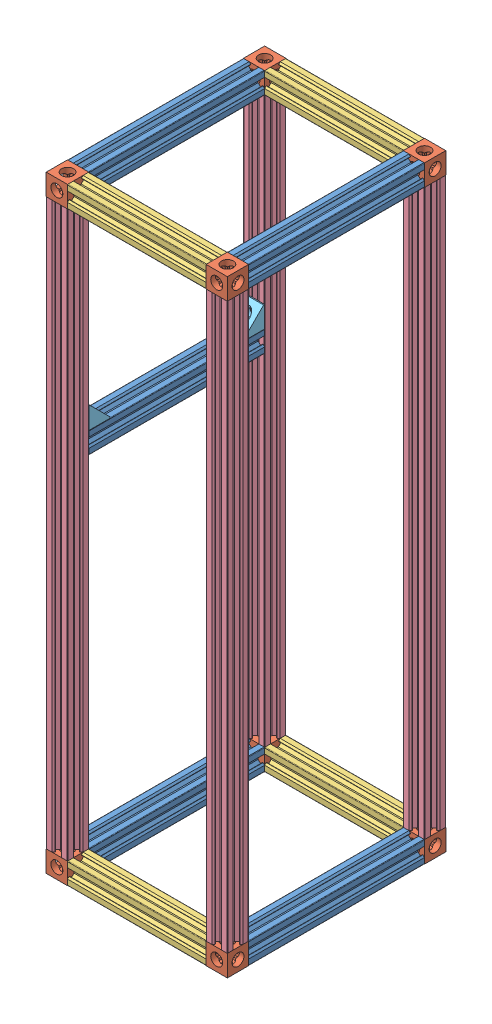
SolidWorks assembly Control Box, configuration Default. Lengths in mm.
Overall size (170 570 205).
23 component instances, 5 part files, 66 mates.
Components (placement in the parent):
- V-Slot 20x20x165-1: V-Slot 20x20x165 [Default] at (106.9043 53.7169 42.2447) size (20 20 165)
- Cube Corner Connector-1: Cube Corner Connector [Default] at (81.3908 81.0191 212.159) size (20 20 20)
- Cube Corner Connector-2: Cube Corner Connector [Default] at (81.3908 81.0191 27.159) size (20 20 20)
- V-Slot 20x20x130-1: V-Slot 20x20x130 [Default] at (-53.5235 53.7169 186.6455) x (0 0 -1) z (1 0 0) size (20 20 130)
- V-Slot 20x20x130-2: V-Slot 20x20x130 [Default] at (-53.5235 53.7169 1.6455) x (0 0 -1) z (1 0 0) size (20 20 130)
- V-Slot 20x20x165-2: V-Slot 20x20x165 [Default] at (-43.0957 53.7169 42.2447) size (20 20 165)
- Cube Corner Connector-3: Cube Corner Connector [Default] at (-68.6092 81.0191 212.159) x (0 1 0) z (0 0 1) size (20 20 20)
- Cube Corner Connector-4: Cube Corner Connector [Default] at (-68.6092 81.0191 27.159) x (0 -1 0) z (0 0 -1) size (20 20 20)
- V-Slot 20x20x530-1: V-Slot 20x20x530 [Default] at (55.142 551.2333 173.9853) x (1 0 0) z (0 -1 0) size (20 20 530)
- V-Slot 20x20x530-2: V-Slot 20x20x530 [Default] at (55.142 551.2333 -11.0147) x (1 0 0) z (0 -1 0) size (20 20 530)
- V-Slot 20x20x530-3: V-Slot 20x20x530 [Default] at (-94.858 160.805 250.3328) x (1 0 0) z (0 1 0) size (20 20 530)
- V-Slot 20x20x530-4: V-Slot 20x20x530 [Default] at (-94.858 160.805 65.3328) x (1 0 0) z (0 1 0) size (20 20 530)
- Cube Corner Connector-5: Cube Corner Connector [Default] at (-68.6092 631.0191 27.159) size (20 20 20)
- Cube Corner Connector-6: Cube Corner Connector [Default] at (-68.6092 631.0191 212.159) x (0 0 1) z (-1 0 0) size (20 20 20)
- Cube Corner Connector-7: Cube Corner Connector [Default] at (81.3908 631.0191 212.159) size (20 20 20)
- Cube Corner Connector-8: Cube Corner Connector [Default] at (81.3908 631.0191 27.159) size (20 20 20)
- V-Slot 20x20x130-3: V-Slot 20x20x130 [Default] at (-53.5235 603.7169 1.6455) x (0 0 -1) z (1 0 0) size (20 20 130)
- V-Slot 20x20x130-4: V-Slot 20x20x130 [Default] at (-53.5235 603.7169 186.6455) x (0 0 -1) z (1 0 0) size (20 20 130)
- V-Slot 20x20x165-3: V-Slot 20x20x165 [Default] at (106.9043 603.7169 42.2447) size (20 20 165)
- V-Slot 20x20x165-4: V-Slot 20x20x165 [Default] at (-43.0957 603.7169 42.2447) size (20 20 165)
- V-Slot 20x20x165-5: V-Slot 20x20x165 [Default] at (-43.0957 393.7169 42.2447) size (20 20 165)
- Black Angle Corner Connector-1: Black Angle Corner Connector [Default] at (-68.6092 441.0191 192.159) x (-1 0 0) z (0 0 -1) size (20 20 20)
- Black Angle Corner Connector-2: Black Angle Corner Connector [Default] at (-68.6092 441.0191 47.159) size (20 20 20)
Mates (geometry in assembly coordinates):
- Coincident1: coincident aligned: plane of V-Slot 20x20x165-1 through (81.3908 91.0191 537.159) normal (0 1 0); plane of Cube Corner Connector-1 through (91.3908 91.0191 222.159) normal (0 1 0)
- Coincident2: coincident aligned: plane of V-Slot 20x20x165-1 through (91.3908 81.0191 537.159) normal (1 0 0); plane of Cube Corner Connector-1 through (91.3908 71.0191 222.159) normal (1 0 0)
- Coincident3: coincident anti-aligned: plane of V-Slot 20x20x165-1 through (71.3908 71.0191 202.159) normal (0 0 1); plane of Cube Corner Connector-1 through (81.3908 81.0191 202.159) normal (0 0 -1)
- Coincident4: coincident anti-aligned: plane of V-Slot 20x20x165-1 through (81.3908 81.0191 37.159) normal (0 0 -1); plane of Cube Corner Connector-2 through (81.3908 81.0191 37.159) normal (0 0 1)
- Coincident5: coincident aligned: plane of V-Slot 20x20x165-1 through (81.3908 91.0191 537.159) normal (0 1 0); plane of Cube Corner Connector-2 through (91.3908 91.0191 37.159) normal (0 1 0)
- Coincident7: coincident aligned: plane of V-Slot 20x20x165-1 through (91.3908 81.0191 537.159) normal (1 0 0); plane of Cube Corner Connector-2 through (91.3908 71.0191 37.159) normal (1 0 0)
- Coincident8: coincident anti-aligned: plane of Cube Corner Connector-1 through (71.3908 71.0191 222.159) normal (-1 0 0); plane of V-Slot 20x20x130-1 through (71.3908 71.0191 222.159) normal (1 0 0)
- Coincident9: coincident aligned: plane of Cube Corner Connector-1 through (81.3908 81.0191 222.159) normal (0 0 1); plane of V-Slot 20x20x130-1 through (441.3908 81.0191 222.159) normal (0 0 1)
- Coincident10: coincident aligned: plane of Cube Corner Connector-1 through (91.3908 91.0191 222.159) normal (0 1 0); plane of V-Slot 20x20x130-1 through (441.3908 91.0191 212.159) normal (0 1 0)
- Coincident11: coincident anti-aligned: plane of Cube Corner Connector-2 through (71.3908 71.0191 37.159) normal (-1 0 0); plane of V-Slot 20x20x130-2 through (71.3908 71.0191 37.159) normal (1 0 0)
- Coincident12: coincident aligned: plane of Cube Corner Connector-2 through (91.3908 91.0191 37.159) normal (0 1 0); plane of V-Slot 20x20x130-2 through (441.3908 91.0191 27.159) normal (0 1 0)
- Coincident13: coincident aligned: plane of Cube Corner Connector-2 through (81.3908 81.0191 17.159) normal (0 0 -1); plane of V-Slot 20x20x130-2 through (441.3908 81.0191 17.159) normal (0 0 -1)
- Coincident14: coincident anti-aligned: plane of V-Slot 20x20x130-1 through (-58.6092 81.0191 212.159) normal (-1 0 0); plane of Cube Corner Connector-3 through (-58.6092 91.0191 222.159) normal (1 0 0)
- Coincident15: coincident aligned: plane of V-Slot 20x20x130-1 through (441.3908 91.0191 212.159) normal (0 1 0); plane of Cube Corner Connector-3 through (-58.6092 91.0191 222.159) normal (0 1 0)
- Coincident16: coincident aligned: plane of V-Slot 20x20x130-1 through (441.3908 81.0191 202.159) normal (0 0 -1); plane of Cube Corner Connector-3 through (-68.6092 81.0191 202.159) normal (0 0 -1)
- Coincident17: coincident aligned: plane of V-Slot 20x20x130-2 through (441.3908 91.0191 27.159) normal (0 1 0); plane of Cube Corner Connector-4 through (-58.6092 91.0191 17.159) normal (0 1 0)
- Coincident19: coincident anti-aligned: plane of V-Slot 20x20x130-2 through (-58.6092 81.0191 27.159) normal (-1 0 0); plane of Cube Corner Connector-4 through (-58.6092 71.0191 17.159) normal (1 0 0)
- Coincident20: coincident aligned: plane of V-Slot 20x20x130-2 through (441.3908 81.0191 37.159) normal (0 0 1); plane of Cube Corner Connector-4 through (-68.6092 81.0191 37.159) normal (0 0 1)
- Coincident21: coincident anti-aligned: plane of V-Slot 20x20x165-2 through (-68.6092 81.0191 37.159) normal (0 0 -1); plane of Cube Corner Connector-4 through (-68.6092 81.0191 37.159) normal (0 0 1)
- Coincident22: coincident aligned: plane of V-Slot 20x20x165-2 through (-68.6092 91.0191 537.159) normal (0 1 0); plane of Cube Corner Connector-4 through (-58.6092 91.0191 17.159) normal (0 1 0)
- Coincident23: coincident aligned: plane of V-Slot 20x20x165-2 through (-78.6092 81.0191 537.159) normal (-1 0 0); plane of Cube Corner Connector-4 through (-78.6092 71.0191 17.159) normal (-1 0 0)
- Coincident24: coincident anti-aligned: plane of Cube Corner Connector-4 through (-58.6092 91.0191 17.159) normal (0 1 0); plane of V-Slot 20x20x530-4 through (-59.1092 91.0191 36.659) normal (0 -1 0)
- Coincident25: coincident aligned: plane of Cube Corner Connector-4 through (-68.6092 81.0191 17.159) normal (0 0 -1); plane of V-Slot 20x20x530-4 through (-68.6092 621.0191 17.159) normal (0 0 -1)
- Coincident26: coincident aligned: plane of Cube Corner Connector-4 through (-78.6092 71.0191 17.159) normal (-1 0 0); plane of V-Slot 20x20x530-4 through (-78.6092 621.0191 27.159) normal (-1 0 0)
- Coincident27: coincident anti-aligned: plane of Cube Corner Connector-3 through (-58.6092 91.0191 222.159) normal (0 1 0); plane of V-Slot 20x20x530-3 through (-59.1092 91.0191 221.659) normal (0 -1 0)
- Coincident28: coincident aligned: plane of Cube Corner Connector-3 through (-78.6092 91.0191 222.159) normal (-1 0 0); plane of V-Slot 20x20x530-3 through (-78.6092 621.0191 212.159) normal (-1 0 0)
- Coincident29: coincident aligned: plane of Cube Corner Connector-3 through (-68.6092 81.0191 222.159) normal (0 0 1); plane of V-Slot 20x20x530-3 through (-68.6092 621.0191 222.159) normal (0 0 1)
- Coincident30: coincident anti-aligned: plane of Cube Corner Connector-1 through (91.3908 91.0191 222.159) normal (0 1 0); plane of V-Slot 20x20x530-1 through (81.3908 91.0191 212.159) normal (0 -1 0)
- Coincident31: coincident aligned: plane of Cube Corner Connector-1 through (71.3908 71.0191 222.159) normal (-1 0 0); plane of V-Slot 20x20x530-1 through (71.3908 91.0191 212.159) normal (-1 0 0)
- Coincident32: coincident aligned: plane of Cube Corner Connector-1 through (81.3908 81.0191 222.159) normal (0 0 1); plane of V-Slot 20x20x530-1 through (81.3908 91.0191 222.159) normal (0 0 1)
- Coincident33: coincident anti-aligned: plane of Cube Corner Connector-2 through (91.3908 91.0191 37.159) normal (0 1 0); plane of V-Slot 20x20x530-2 through (81.3908 91.0191 27.159) normal (0 -1 0)
- Coincident34: coincident aligned: plane of Cube Corner Connector-2 through (81.3908 81.0191 17.159) normal (0 0 -1); plane of V-Slot 20x20x530-2 through (81.3908 91.0191 17.159) normal (0 0 -1)
- Coincident35: coincident aligned: plane of Cube Corner Connector-2 through (91.3908 71.0191 37.159) normal (1 0 0); plane of V-Slot 20x20x530-2 through (91.3908 91.0191 27.159) normal (1 0 0)
- Coincident36: coincident aligned: plane of V-Slot 20x20x530-4 through (-68.6092 621.0191 17.159) normal (0 0 -1); plane of Cube Corner Connector-5 through (-68.6092 631.0191 17.159) normal (0 0 -1)
- Coincident37: coincident aligned: plane of V-Slot 20x20x530-4 through (-78.6092 621.0191 27.159) normal (-1 0 0); plane of Cube Corner Connector-5 through (-78.6092 621.0191 37.159) normal (-1 0 0)
- Coincident38: coincident anti-aligned: plane of V-Slot 20x20x530-4 through (-68.6092 621.0191 27.159) normal (0 1 0); plane of Cube Corner Connector-5 through (-58.6092 621.0191 37.159) normal (0 -1 0)
- Coincident40: coincident anti-aligned: plane of V-Slot 20x20x530-3 through (-68.6092 621.0191 212.159) normal (0 1 0); plane of Cube Corner Connector-6 through (-78.6092 621.0191 222.159) normal (0 -1 0)
- Coincident41: coincident aligned: plane of V-Slot 20x20x530-3 through (-78.6092 621.0191 212.159) normal (-1 0 0); plane of Cube Corner Connector-6 through (-78.6092 631.0191 212.159) normal (-1 0 0)
- Coincident42: coincident aligned: plane of V-Slot 20x20x530-3 through (-68.6092 621.0191 202.159) normal (0 0 -1); plane of Cube Corner Connector-6 through (-78.6092 621.0191 202.159) normal (0 0 -1)
- Coincident43: coincident aligned: plane of V-Slot 20x20x530-1 through (81.3908 91.0191 202.159) normal (0 0 -1); plane of Cube Corner Connector-7 through (81.3908 631.0191 202.159) normal (0 0 -1)
- Coincident44: coincident aligned: plane of V-Slot 20x20x530-1 through (71.3908 91.0191 212.159) normal (-1 0 0); plane of Cube Corner Connector-7 through (71.3908 621.0191 222.159) normal (-1 0 0)
- Coincident45: coincident anti-aligned: plane of V-Slot 20x20x530-1 through (90.8908 621.0191 202.659) normal (0 1 0); plane of Cube Corner Connector-7 through (91.3908 621.0191 222.159) normal (0 -1 0)
- Coincident46: coincident aligned: plane of V-Slot 20x20x530-2 through (81.3908 91.0191 17.159) normal (0 0 -1); plane of Cube Corner Connector-8 through (81.3908 631.0191 17.159) normal (0 0 -1)
- Coincident47: coincident aligned: plane of V-Slot 20x20x530-2 through (71.3908 91.0191 27.159) normal (-1 0 0); plane of Cube Corner Connector-8 through (71.3908 621.0191 37.159) normal (-1 0 0)
- Coincident48: coincident anti-aligned: plane of V-Slot 20x20x530-2 through (90.8908 621.0191 17.659) normal (0 1 0); plane of Cube Corner Connector-8 through (91.3908 621.0191 37.159) normal (0 -1 0)
- Coincident49: coincident anti-aligned: plane of Cube Corner Connector-5 through (-58.6092 621.0191 37.159) normal (1 0 0); plane of V-Slot 20x20x130-3 through (-58.6092 631.0191 27.159) normal (-1 0 0)
- Coincident50: coincident aligned: plane of Cube Corner Connector-5 through (-68.6092 631.0191 17.159) normal (0 0 -1); plane of V-Slot 20x20x130-3 through (441.3908 631.0191 17.159) normal (0 0 -1)
- Coincident51: coincident aligned: plane of Cube Corner Connector-5 through (-58.6092 641.0191 37.159) normal (0 1 0); plane of V-Slot 20x20x130-3 through (441.3908 641.0191 27.159) normal (0 1 0)
- Coincident52: coincident aligned: plane of Cube Corner Connector-6 through (-78.6092 641.0191 222.159) normal (0 1 0); plane of V-Slot 20x20x130-4 through (441.3908 641.0191 212.159) normal (0 1 0)
- Coincident53: coincident anti-aligned: plane of Cube Corner Connector-6 through (-58.6092 631.0191 212.159) normal (1 0 0); plane of V-Slot 20x20x130-4 through (-58.6092 631.0191 212.159) normal (-1 0 0)
- Coincident54: coincident aligned: plane of Cube Corner Connector-6 through (-78.6092 621.0191 202.159) normal (0 0 -1); plane of V-Slot 20x20x130-4 through (441.3908 631.0191 202.159) normal (0 0 -1)
- Coincident55: coincident anti-aligned: plane of Cube Corner Connector-5 through (-68.6092 631.0191 37.159) normal (0 0 1); plane of V-Slot 20x20x165-4 through (-68.6092 631.0191 37.159) normal (0 0 -1)
- Coincident56: coincident aligned: plane of Cube Corner Connector-5 through (-78.6092 621.0191 37.159) normal (-1 0 0); plane of V-Slot 20x20x165-4 through (-78.6092 631.0191 537.159) normal (-1 0 0)
- Coincident57: coincident aligned: plane of Cube Corner Connector-5 through (-58.6092 641.0191 37.159) normal (0 1 0); plane of V-Slot 20x20x165-4 through (-68.6092 641.0191 537.159) normal (0 1 0)
- Coincident58: coincident aligned: plane of Cube Corner Connector-8 through (91.3908 641.0191 37.159) normal (0 1 0); plane of V-Slot 20x20x165-3 through (81.3908 641.0191 537.159) normal (0 1 0)
- Coincident59: coincident aligned: plane of Cube Corner Connector-8 through (71.3908 621.0191 37.159) normal (-1 0 0); plane of V-Slot 20x20x165-3 through (71.3908 631.0191 537.159) normal (-1 0 0)
- Coincident60: coincident anti-aligned: plane of Cube Corner Connector-7 through (81.3908 631.0191 202.159) normal (0 0 -1); plane of V-Slot 20x20x165-3 through (71.3908 621.0191 202.159) normal (0 0 1)
- Coincident61: coincident anti-aligned: plane of V-Slot 20x20x530-3 through (-68.6092 621.0191 202.159) normal (0 0 -1); plane of V-Slot 20x20x165-5 through (-78.6092 411.0191 202.159) normal (0 0 1)
- Coincident62: coincident aligned: plane of V-Slot 20x20x530-4 through (-78.6092 621.0191 27.159) normal (-1 0 0); plane of V-Slot 20x20x165-5 through (-78.6092 421.0191 537.159) normal (-1 0 0)
- Distance1: distance = 190 mm anti-aligned: plane of V-Slot 20x20x165-4 through (-68.6092 621.0191 537.159) normal (0 -1 0); plane of V-Slot 20x20x165-5 through (-68.6092 431.0191 537.159) normal (0 1 0)
- Coincident64: coincident anti-aligned: plane of V-Slot 20x20x530-4 through (-68.6092 621.0191 37.159) normal (0 0 1); plane of Black Angle Corner Connector-2 through (-68.6092 441.0191 37.159) normal (0 0 -1)
- Coincident65: coincident aligned: plane of V-Slot 20x20x165-5 through (-78.6092 421.0191 537.159) normal (-1 0 0); plane of Black Angle Corner Connector-2 through (-78.6092 431.0191 57.159) normal (-1 0 0)
- Coincident66: coincident anti-aligned: plane of V-Slot 20x20x165-5 through (-68.6092 431.0191 537.159) normal (0 1 0); plane of Black Angle Corner Connector-2 through (-58.6092 431.0191 57.159) normal (0 -1 0)
- Coincident67: coincident anti-aligned: plane of V-Slot 20x20x530-3 through (-68.6092 621.0191 202.159) normal (0 0 -1); plane of Black Angle Corner Connector-1 through (54.0379 441.0191 202.159) normal (0 0 1)
- Coincident68: coincident anti-aligned: plane of V-Slot 20x20x165-5 through (-68.6092 431.0191 537.159) normal (0 1 0); plane of Black Angle Corner Connector-1 through (44.0379 431.0191 182.159) normal (0 -1 0)
- Coincident69: coincident aligned: plane of V-Slot 20x20x165-5 through (-78.6092 421.0191 537.159) normal (-1 0 0); plane of Black Angle Corner Connector-1 through (-78.6092 431.0191 182.159) normal (-1 0 0)
